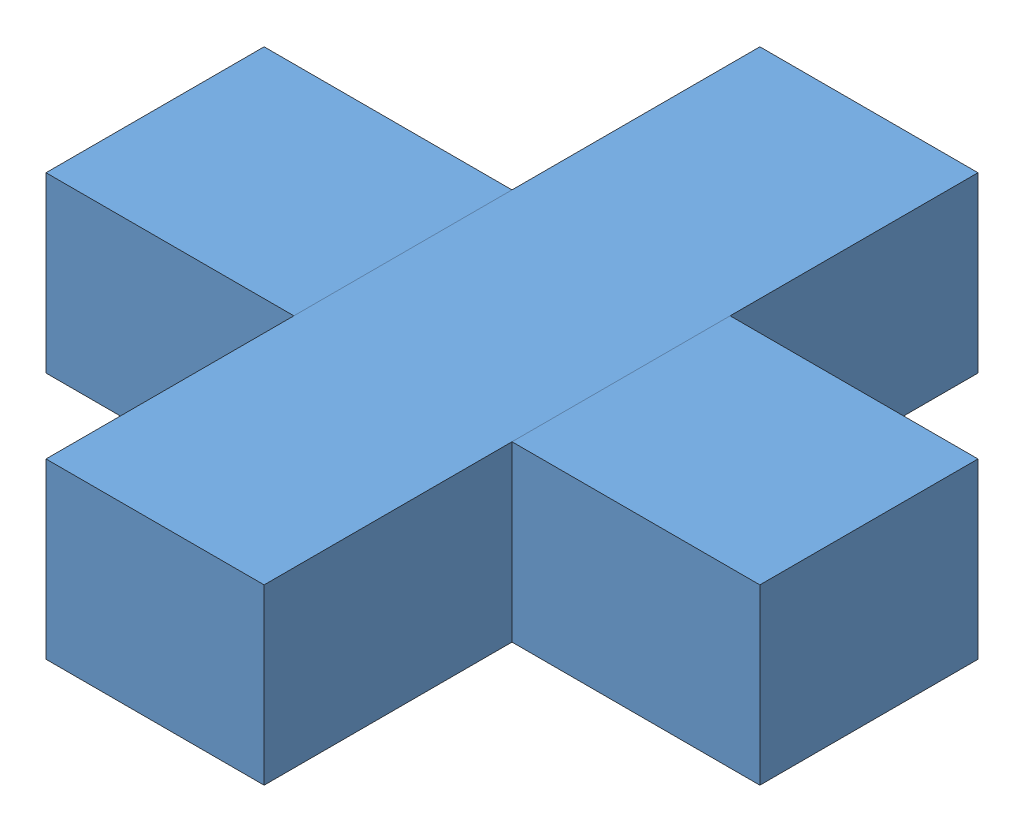
SolidWorks assembly CROSS H ASS, configuration Default. Lengths in mm.
Overall size (144 35 144).
2 component instances, 1 part files, 3 mates.
Components (placement in the parent):
- CROSS HALVING-1: CROSS HALVING [Default] at (-122.4608 41.0705 -22) size (144 35 44)
- CROSS HALVING-2: CROSS HALVING [Default] at (-28.4608 76.0705 72) x (0 0 -1) z (-1 0 0) size (144 35 44)
Mates (geometry in assembly coordinates):
- Coincident11: coincident anti-aligned: plane of CROSS HALVING-1 through (-72.4608 58.5705 22) normal (0 1 0)
- Coincident12: coincident anti-aligned: line of CROSS HALVING-1 through (-28.4608 58.5705 22) axis (-1 0 0); line of CROSS HALVING-2 through (-72.4608 58.5705 22) axis (1 0 0)
- Coincident13: coincident anti-aligned: line of CROSS HALVING-1 through (-28.4608 58.5705 22) axis (0 0 -1); line of CROSS HALVING-2 through (-28.4608 58.5705 -22) axis (0 0 1)
